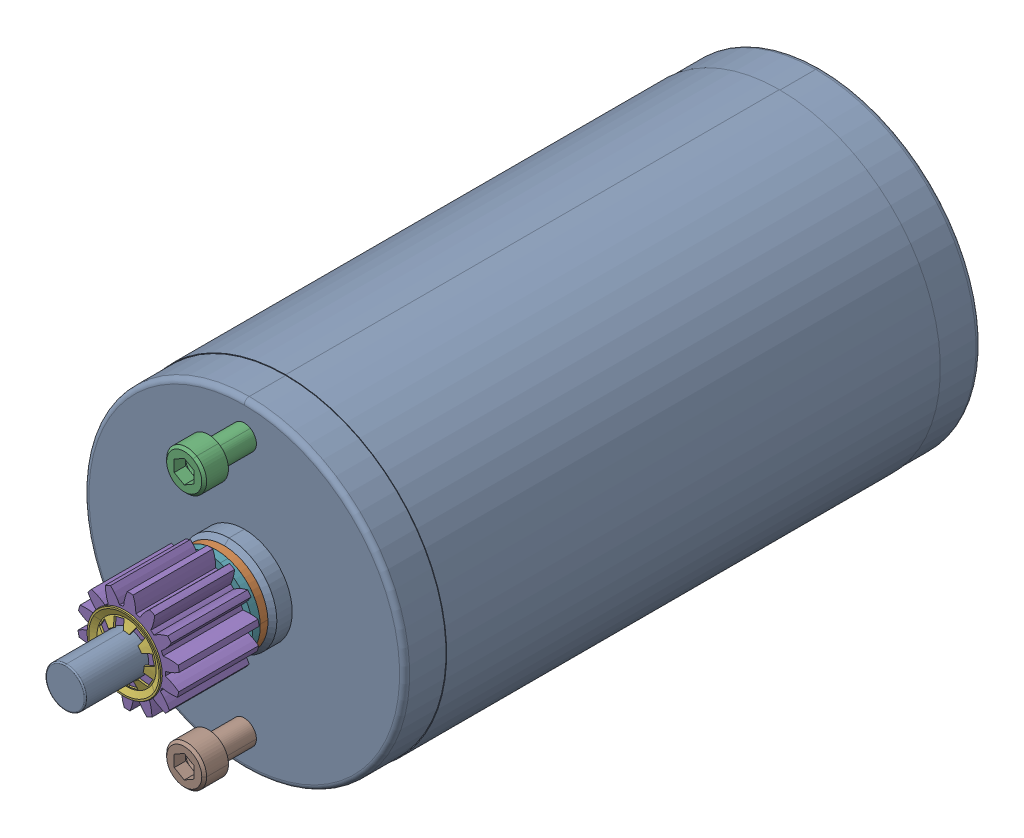
SolidWorks assembly CIM for ToughBox Gearboxes, configuration Default. Lengths in mm.
Overall size (64.01 64.01 154.93).
8 component instances, 6 part files, 6 mates.
Components (placement in the parent):
- am-0255 CIM Motor-1: am-0255 CIM Motor [Default] at (-109.2962 39.56 -19.05) x (0 -1 0) z (0 0 1) size (64.01 64.01 154.93)
- am-1009 5-16 flat washer-1: am-1009 5-16 flat washer [Default] at (0 4 4.064) x (0.999201 0.039961 0) z (0 0 1) size (17.53 17.53 1.52)
- am-1120 10-32 x 0625 SHCS with Thread Patch_HX-SHCS 0.19-32x1.375x1-C-1: am-1120 10-32 x 0625 SHCS with Thread Patch_HX-SHCS 0.19-32x1.375x1-C [Default] at (0 29.4 11.938) x (0 0 -1) z (0.5 0.866025 0) size (20.7 7.94 7.94)
- am-1121 2mm x 2mm x 10mm Machine Key-1: am-1121 2mm x 2mm x 10mm Machine Key [Default] at (5.342 4.9946 24.0495) x (0 0 -1) z (0.599127 -0.800654 0) size (10 2 2)
- 14T CIM Gear-1: 14T CIM Gear [Default] at (0 4 7.112) x (0.599127 -0.800654 0) z (0 0 1) size (20.03 20.32 15.88)
- am-0033 8mm Push-On Retaining Ring-1: am-0033 8mm Push-On Retaining Ring [Default] at (0 4 22.987) x (0 0 1) z (-0.860772 0.508991 0) size (1.07 14.83 14.83)
- am-1009 5-16 flat washer-2: am-1009 5-16 flat washer [Default] at (0 4 5.588) x (0.266919 0.963719 0) z (0 0 1) size (17.53 17.53 1.52)
- am-1120 10-32 x 0625 SHCS with Thread Patch_HX-SHCS 0.19-32x1.375x1-C-2: am-1120 10-32 x 0625 SHCS with Thread Patch_HX-SHCS 0.19-32x1.375x1-C [Default] at (0 -21.4 11.938) x (0 0 -1) z (1 0 0) size (20.7 7.94 7.94)
Mates (geometry in assembly coordinates):
- Coincident1: coincident anti-aligned: plane of 14T CIM Gear-1 through (0 4 7.112) normal (0 0 -1); plane of am-1009 5-16 flat washer-2 through (0 4 7.112) normal (0 0 1)
- Coincident2: coincident anti-aligned: plane of am-1121 2mm x 2mm x 10mm Machine Key-1 through (2.8994 4.9206 20.0495) normal (0.599127 -0.800654 0); plane of 14T CIM Gear-1 through (3.0011 4.9967 19.812) normal (-0.599127 0.800654 0)
- Concentric1: concentric aligned: cylinder of am-0255 CIM Motor-1 through (0 4 35.564) axis (0 0 -1) radius 4; cylinder of 14T CIM Gear-1 through (0 4 19.812) axis (0 0 -1) radius 4
- Coincident3: coincident: cylinder of am-0255 CIM Motor-1 through (0 4 35.564) axis (0 0 -1) radius 4; point of am-1121 2mm x 2mm x 10mm Machine Key-1
- Coincident4: coincident: cylinder of am-0255 CIM Motor-1 through (0 4 35.564) axis (0 0 -1) radius 4
- Width1: width aligned: plane of am-1121 2mm x 2mm x 10mm Machine Key-1 through (1.7011 6.5219 20.0495) normal (0 0 1); plane of 14T CIM Gear-1 through (2.8994 4.9206 10.0495) normal (0 0 -1); plane of am-1121 2mm x 2mm x 10mm Machine Key-1 through (4.8568 5.324 22.987) normal (0 0 1); plane of 14T CIM Gear-1 through (0 4 7.112) normal (0 0 -1)
